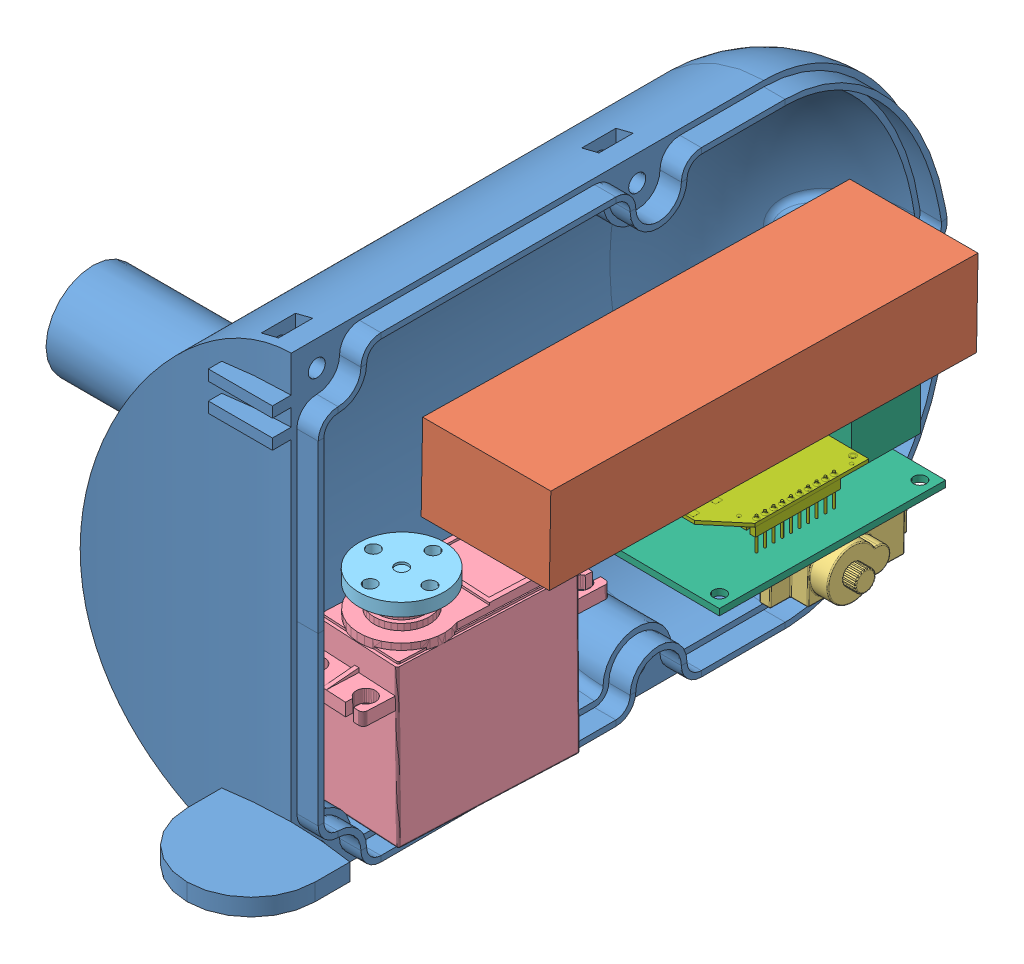
SolidWorks assembly FishAssm, configuration Default. Lengths in mm.
Overall size (85.42 115.56 178.36).
10 component instances, 7 part files, 5 mates.
Components (placement in the parent):
- Body_v3-1: Body_v3 [Default] at (71.2529 103.4009 201.2273) size (97.38 115.86 178.36)
- Battery-1: Battery [Default] at (85.9362 118.8702 110.9386) x (0 0.017452 0.999848) z (1 0 0) size (100 20 30)
- MicroServo-2: MicroServo [Default] at (71.2529 74.5038 81.8358) x (0 0.017452 0.999848) z (0 0.999848 -0.017452) size (40.02 29.7 12.14)
- Servo and metal horn v1-1: Servo and metal horn v1 [Default] at (73.7552 54.9314 107.38) x (-0.99863 0 -0.052336) z (0.052334 0.008727 -0.998592) size (20 47.3 55.02)
  - servo v7-1: servo v7 [Default] at (0 -3 -26) size (20 46.8 55.02)
    - Component3-1: Component3 [Default] at origin size (20 46.8 55.02)
  - servo metal horn-1: servo metal horn [Default] at (0.0023 47.1264 -67.7367) x (1 0 0) z (0 0 -1) size (20 4.5 20)
- XbeeAss-1: XbeeAss [Default] at (25.4046 56.9793 85.59) x (0.008727 0 -0.999962) z (0.999962 0 0.008727) size (59 18.15 36.5)
  - Xbee-1: Xbee [Default] at (-9.0332 27.9523 57.8118) size (59 12 36.5)
  - XBeeProS1-1: XBeeProS1 [Default] at (-14.4916 35.5123 57.8118) size (32.94 16.65 23.73)
Mates (geometry in assembly coordinates):
- Parallel7: parallel aligned: plane of Body_v3-1 through (71.2529 103.4009 201.2273) normal (-1 0 0); plane of MicroServo-2 through (71.2529 74.5038 81.8358) normal (-1 0 0)
- Coincident6: coincident aligned: plane of Body_v3-1 through (71.2529 103.4009 201.2273) normal (-1 0 0); plane of MicroServo-2 through (71.2529 74.5038 81.8358) normal (-1 0 0)
- Coincident7: coincident: face of Body_v3-1; point of Battery-1
- Parallel8: parallel aligned: plane of Body_v3-1 through (71.2529 103.4009 201.2273) normal (-1 0 0); plane of Battery-1 through (70.9362 107.9991 61.1207) normal (-1 0 0)
- Parallel10: parallel anti-aligned: plane of Battery-1 through (85.9362 108.8717 111.1131) normal (0 -0.999848 0.017452); plane of MicroServo-2 through (71.2529 80.3513 70.4544) normal (0 0.999848 -0.017452)
